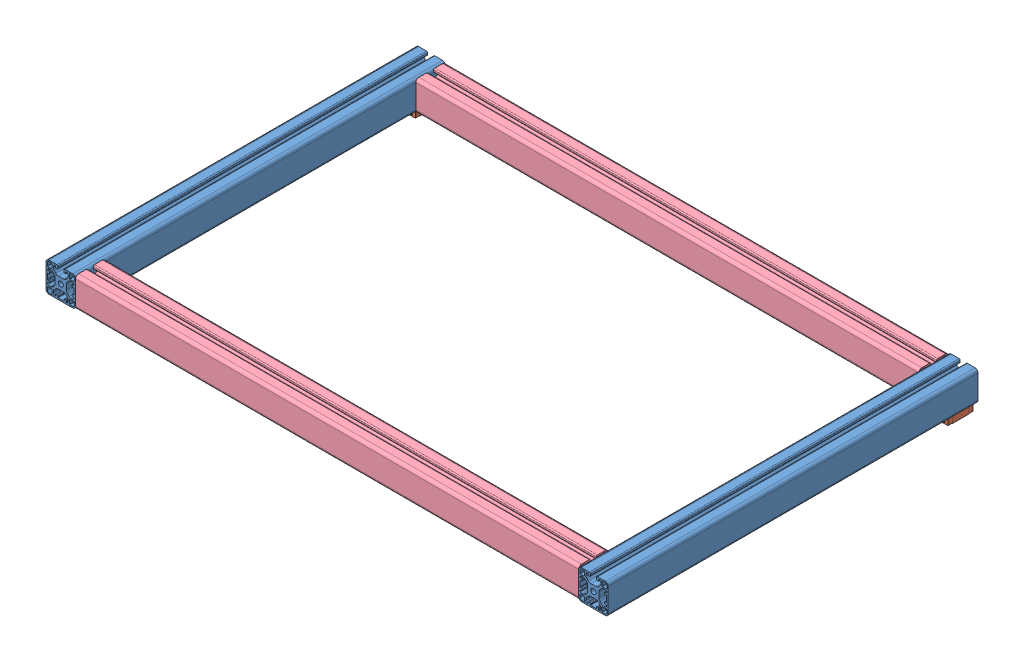
SolidWorks assembly y-axis-assembled, configuration Standard. Lengths in mm.
Overall size (760 53 500.99).
10 component instances, 4 part files, 15 mates.
Components (placement in the parent):
- y-axis-iType-40x40-profile-1: y-axis-iType-40x40-profile [Standard] at (-23.5065 -20.2928 -250) size (40 40 500)
- MGN12C 1 R 400 ZF H M SS_FILE-1: MGN12C 1 R 400 ZF H M SS_FILE [Standard] at (12.7413 -22.1323 287.5) x (1 0 0) z (0 -1 0) size (27 400 13) (flexible)
  - MGN12C 1 R 400 ZF H M SS_FILE-1: MGN12C 1 R 400 ZF H M SS_FILE [Standard] at (-20.2479 -37.55 -1.8395) size (27 35.69 10)
  - MGN12C 1 R 400 ZF H M SS_FILE_1-1: MGN12C 1 R 400 ZF H M SS_FILE_1 [Standard] at (-20.2479 0 -1.8395) size (12 400 8)
- y-axis-iType-40x40-profile-2: y-axis-iType-40x40-profile [Standard] at (696.4935 -20.2928 -250) size (40 40 500)
- strebe_40x40_570-1: strebe_40x40_570 [Standard] at (692.4935 -20.2928 714) x (0 0 1) z (-1 0 0) size (40 40 680)
- strebe_40x40_570-2: strebe_40x40_570 [Standard] at (692.4935 -20.2928 254) x (0 0 1) z (-1 0 0) size (40 40 680)
- MGN12C 1 R 400 ZF H M SS_FILE-2: MGN12C 1 R 400 ZF H M SS_FILE [Standard] at (709.6425 -35.6431 287.5) x (1 0 0) z (0 -1 0) size (27 400 13) (flexible)
  - MGN12C 1 R 400 ZF H M SS_FILE-1: MGN12C 1 R 400 ZF H M SS_FILE [Standard] at (2.8509 -37.55 -15.3502) size (27 35.69 10)
  - MGN12C 1 R 400 ZF H M SS_FILE_1-1: MGN12C 1 R 400 ZF H M SS_FILE_1 [Standard] at (2.8509 0 -15.3502) size (12 400 8)
Mates (geometry in assembly coordinates):
- Konzentrisch1: concentric anti-aligned: cylinder of y-axis-iType-40x40-profile-1 through (-7.5065 -20.2928 300) axis (0 -1 0) radius 1.25; cylinder of MGN12C 1 R 400 ZF H M SS_FILE-1/MGN12C 1 R 400 ZF H M SS_FILE_1-1 through (-7.5065 -22.0428 300) axis (0 1 0) radius 1.75
- Deckungsgleich1: coincident anti-aligned: plane of y-axis-iType-40x40-profile-1 through (-23.5065 -20.2928 250) normal (0 -1 0); plane of MGN12C 1 R 400 ZF H M SS_FILE-1/MGN12C 1 R 400 ZF H M SS_FILE_1-1 through (-2.0065 -20.2928 687.5) normal (0 1 0)
- Konzentrisch2: concentric anti-aligned: cylinder of y-axis-iType-40x40-profile-1 through (-7.5065 -20.2928 675) axis (0 -1 0) radius 1.25; cylinder of MGN12C 1 R 400 ZF H M SS_FILE-1/MGN12C 1 R 400 ZF H M SS_FILE_1-1 through (-7.5065 -22.0428 675) axis (0 1 0) radius 1.75
- Deckungsgleich2: coincident anti-aligned: plane of y-axis-iType-40x40-profile-1 through (12.4935 -16.2928 250) normal (1 0 0); plane of strebe_40x40_570-1 through (12.4935 15.5572 736.6) normal (-1 0 0)
- Deckungsgleich3: coincident aligned: plane of y-axis-iType-40x40-profile-1 through (-23.5065 -20.2928 250) normal (0 -1 0); plane of strebe_40x40_570-1 through (692.4935 -20.2928 714) normal (0 -1 0)
- Deckungsgleich4: coincident aligned: plane of y-axis-iType-40x40-profile-2 through (696.4935 -20.2928 250) normal (0 -1 0); plane of strebe_40x40_570-1 through (692.4935 -20.2928 714) normal (0 -1 0)
- Deckungsgleich5: coincident anti-aligned: plane of y-axis-iType-40x40-profile-2 through (692.4935 15.7072 250) normal (-1 0 0); plane of strebe_40x40_570-1 through (692.4935 15.5572 736.6) normal (1 0 0)
- Deckungsgleich6: coincident aligned: plane of y-axis-iType-40x40-profile-2 through (719.0935 15.5572 750) normal (0 0 1); plane of strebe_40x40_570-1 through (692.4935 -16.2928 750) normal (0 0 1)
- Deckungsgleich7: coincident aligned: plane of y-axis-iType-40x40-profile-1 through (-0.9065 15.5572 750) normal (0 0 1); plane of strebe_40x40_570-1 through (692.4935 -16.2928 750) normal (0 0 1)
- Deckungsgleich8: coincident aligned: plane of y-axis-iType-40x40-profile-1 through (-23.5065 -20.2928 250) normal (0 -1 0); plane of strebe_40x40_570-2 through (692.4935 -20.2928 254) normal (0 -1 0)
- Deckungsgleich9: coincident anti-aligned: plane of y-axis-iType-40x40-profile-1 through (12.4935 -16.2928 250) normal (1 0 0); plane of strebe_40x40_570-2 through (12.4935 15.5572 276.6) normal (-1 0 0)
- Deckungsgleich10: coincident aligned: plane of y-axis-iType-40x40-profile-1 through (-0.9065 15.5572 250) normal (0 0 -1); plane of strebe_40x40_570-2 through (692.4935 15.7072 250) normal (0 0 -1)
- Konzentrisch3: concentric anti-aligned: cylinder of y-axis-iType-40x40-profile-2 through (712.4935 -20.2928 300) axis (0 -1 0) radius 1.25; cylinder of MGN12C 1 R 400 ZF H M SS_FILE-2/MGN12C 1 R 400 ZF H M SS_FILE_1-1 through (712.4935 -22.0428 300) axis (0 1 0) radius 1.75
- Konzentrisch4: concentric anti-aligned: cylinder of y-axis-iType-40x40-profile-2 through (712.4935 -20.2928 675) axis (0 -1 0) radius 1.25; cylinder of MGN12C 1 R 400 ZF H M SS_FILE-2/MGN12C 1 R 400 ZF H M SS_FILE_1-1 through (712.4935 -22.0428 675) axis (0 1 0) radius 1.75
- Deckungsgleich11: coincident anti-aligned: plane of y-axis-iType-40x40-profile-2 through (696.4935 -20.2928 250) normal (0 -1 0); plane of MGN12C 1 R 400 ZF H M SS_FILE-2/MGN12C 1 R 400 ZF H M SS_FILE_1-1 through (717.9935 -20.2928 687.5) normal (0 1 0)
